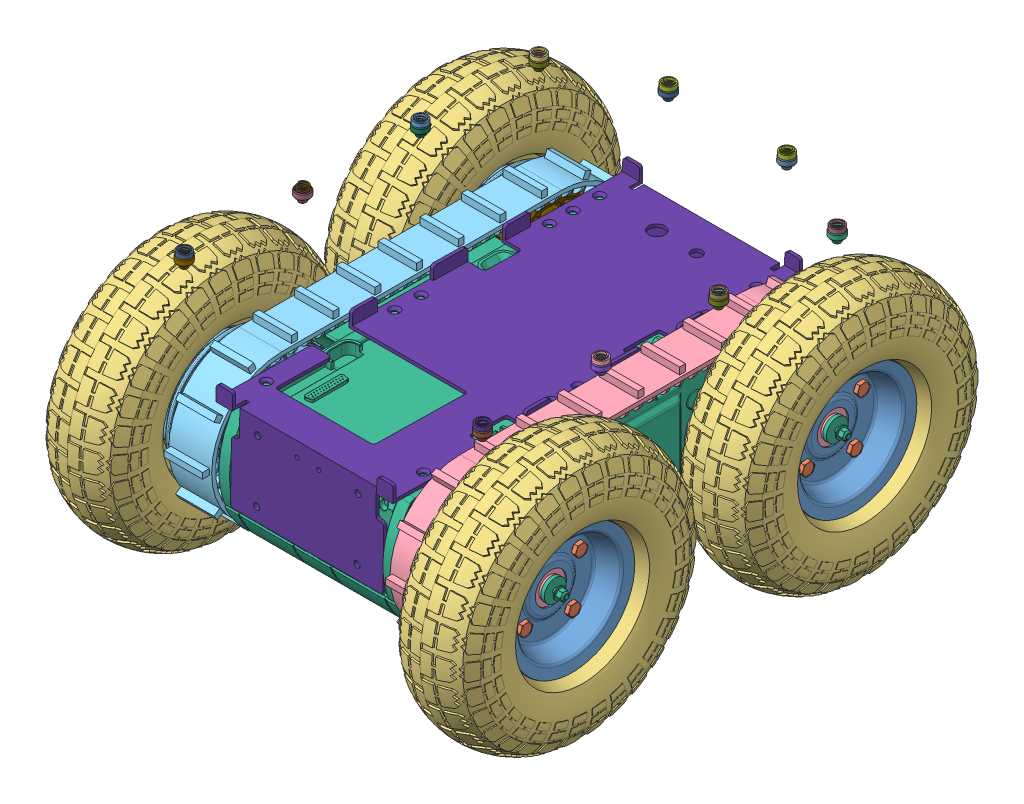
SolidWorks assembly RD_Payload_Rev_A, configuration Default. Lengths in mm.
Overall size (444.69 367.29 650.79).
94 component instances, 59 part files, 0 mates.
Components (placement in the parent):
- RD_Payload_Rev_A.step-1: RD_Payload_Rev_A.step [Default] at origin size (444.69 371.55 650.79)
  - 10 in Wheel.step-1: 10 in Wheel.step [Default] at (178.555 0 0) x (0 -0.59872 0.800958) z (-1 0 0) size (260.79 263.33 83.58)
    - Hub Outer.step-1: Hub Outer.step [Default] x (1 0 0) z (0 0 -1) size (127 127 25.4)
    - Bolt M8x14mm.step-1: Bolt M8x14mm.step [Default] at (0 34.925 -7.0104) x (1 0 0) z (0 -1 0) size (11.71 18.58 13.52)
    - Bolt M8x14mm.step-2: Bolt M8x14mm.step [Default] at (-34.925 0 -7.0104) x (1 0 0) z (0 -1 0) size (11.71 18.58 13.52)
    - Bolt M8x14mm.step-3: Bolt M8x14mm.step [Default] at (0 -34.925 -7.0104) x (1 0 0) z (0 -1 0) size (11.71 18.58 13.52)
    - Bolt M8x14mm.step-4: Bolt M8x14mm.step [Default] at (34.925 0 -7.0104) x (1 0 0) z (0 -1 0) size (11.71 18.58 13.52)
    - Tire.step-1: Tire.step [Default] x (0 0 -1) z (-0.99993 -0.011854 0) size (83.58 260.3 257.72)
    - Bearing.step-1: Bearing.step [Default] at (0 0 -2.159) x (0.59872 -0.800958 0) z (0 0 -1) size (37.59 37.59 12.4)
    - ModifiedWheelHub.step-1: ModifiedWheelHub.step [Default] at (-0.127 0 22.847) x (0 0 -1) z (1 0 0) size (30.5 125 125)
  - 10 in Wheel_1.step-1: 10 in Wheel_1.step [Default] at (180.555 0 -283.5) x (0 -0.59872 0.800958) z (-1 0 0) size (260.79 263.33 83.58)
    - Hub Outer.step-1: Hub Outer.step [Default] x (1 0 0) z (0 0 -1) size (127 127 25.4)
    - Bolt M8x14mm.step-1: Bolt M8x14mm.step [Default] at (0 34.925 -7.0104) x (1 0 0) z (0 -1 0) size (11.71 18.58 13.52)
    - Bolt M8x14mm.step-2: Bolt M8x14mm.step [Default] at (-34.925 0 -7.0104) x (1 0 0) z (0 -1 0) size (11.71 18.58 13.52)
    - Bolt M8x14mm.step-3: Bolt M8x14mm.step [Default] at (0 -34.925 -7.0104) x (1 0 0) z (0 -1 0) size (11.71 18.58 13.52)
    - Bolt M8x14mm.step-4: Bolt M8x14mm.step [Default] at (34.925 0 -7.0104) x (1 0 0) z (0 -1 0) size (11.71 18.58 13.52)
    - Tire.step-1: Tire.step [Default] x (0 0 -1) z (-0.99993 -0.011854 0) size (83.58 260.3 257.72)
    - Bearing.step-1: Bearing.step [Default] at (0 0 -2.159) x (0.59872 -0.800958 0) z (0 0 -1) size (37.59 37.59 12.4)
    - ModifiedWheelHub.step-1: ModifiedWheelHub.step [Default] at (-0.127 0 22.847) x (0 0 -1) z (1 0 0) size (30.5 125 125)
  - 10 in Wheel_2.step-1: 10 in Wheel_2.step [Default] at (-180.555 0 -283.5) x (0 -0.800958 0.59872) z (1 0 0) size (260.79 263.33 83.58)
    - Hub Outer.step-1: Hub Outer.step [Default] x (1 0 0) z (0 0 -1) size (127 127 25.4)
    - Bolt M8x14mm.step-1: Bolt M8x14mm.step [Default] at (0 34.925 -7.0104) x (1 0 0) z (0 -1 0) size (11.71 18.58 13.52)
    - Bolt M8x14mm.step-2: Bolt M8x14mm.step [Default] at (-34.925 0 -7.0104) x (1 0 0) z (0 -1 0) size (11.71 18.58 13.52)
    - Bolt M8x14mm.step-3: Bolt M8x14mm.step [Default] at (0 -34.925 -7.0104) x (1 0 0) z (0 -1 0) size (11.71 18.58 13.52)
    - Bolt M8x14mm.step-4: Bolt M8x14mm.step [Default] at (34.925 0 -7.0104) x (1 0 0) z (0 -1 0) size (11.71 18.58 13.52)
    - Tire.step-1: Tire.step [Default] x (0 0 -1) z (-0.99993 -0.011854 0) size (83.58 260.3 257.72)
    - Bearing.step-1: Bearing.step [Default] at (0 0 -2.159) x (0.59872 -0.800958 0) z (0 0 -1) size (37.59 37.59 12.4)
    - ModifiedWheelHub.step-1: ModifiedWheelHub.step [Default] at (-0.127 0 22.847) x (0 0 -1) z (1 0 0) size (30.5 125 125)
  - 10 in Wheel_3.step-1: 10 in Wheel_3.step [Default] at (-178.555 0 0) x (0 -0.800958 0.59872) z (1 0 0) size (260.79 263.33 83.58)
    - Hub Outer.step-1: Hub Outer.step [Default] x (1 0 0) z (0 0 -1) size (127 127 25.4)
    - Bolt M8x14mm.step-1: Bolt M8x14mm.step [Default] at (0 34.925 -7.0104) x (1 0 0) z (0 -1 0) size (11.71 18.58 13.52)
    - Bolt M8x14mm.step-2: Bolt M8x14mm.step [Default] at (-34.925 0 -7.0104) x (1 0 0) z (0 -1 0) size (11.71 18.58 13.52)
    - Bolt M8x14mm.step-3: Bolt M8x14mm.step [Default] at (0 -34.925 -7.0104) x (1 0 0) z (0 -1 0) size (11.71 18.58 13.52)
    - Bolt M8x14mm.step-4: Bolt M8x14mm.step [Default] at (34.925 0 -7.0104) x (1 0 0) z (0 -1 0) size (11.71 18.58 13.52)
    - Tire.step-1: Tire.step [Default] x (0 0 -1) z (-0.99993 -0.011854 0) size (83.58 260.3 257.72)
    - Bearing.step-1: Bearing.step [Default] at (0 0 -2.159) x (0.59872 -0.800958 0) z (0 0 -1) size (37.59 37.59 12.4)
    - ModifiedWheelHub.step-1: ModifiedWheelHub.step [Default] at (-0.127 0 22.847) x (0 0 -1) z (1 0 0) size (30.5 125 125)
  - R&D Payload.step-1: R&D Payload.step [Default] at (7.0458 -116.5686 -486.2193) x (1 0 0) z (0 0.999848 -0.017452) size (435.85 572.37 235.56)
    - R&D Payload Assembly (approx, don't use) v9.step-1: R&D Payload Assembly (approx, don't use) v9.step [Default] at (0 0 150) size (435.85 572.37 129.48)
      - PPatrol Payload v6.step-1: PPatrol Payload v6.step [Default] at (200.9785 -625.114 143.2331) x (0 -1 0) z (-1 0 0) size (572.37 31.75 435.85)
        - 8020-1010-BLACK-1010-BLACK X 72 v1.step-1: 8020-1010-BLACK-1010-BLACK X 72 v1.step [Default] at (-12.6721 -12.7 413.3053) size (25.4 25.4 387.35) (hidden)
        - 8020-1010-BLACK-1010-BLACK X 72 v1 (1).step-1: 8020-1010-BLACK-1010-BLACK X 72 v1 (1).step [Default] at (-25.3721 -12.7 400.6053) x (0 0 -1) z (1 0 0) size (25.4 25.4 523.88) (hidden)
        - 8020-1010-BLACK-1010-BLACK X 72 v1 (2).step-1: 8020-1010-BLACK-1010-BLACK X 72 v1 (2).step [Default] at (-536.5471 -12.7 387.9053) size (25.4 25.4 387.35) (hidden)
        - 8020-1010-BLACK-1010-BLACK X 72 v1 (1) (1).step-1: 8020-1010-BLACK-1010-BLACK X 72 v1 (1) (1).step [Default] at (-637.3851 -12.7 -418.5447) x (0 0 1) z (-1 0 0) size (25.4 25.4 523.88) (hidden)
        - Polycarbonate.step-1: Polycarbonate.step [Default] at origin size (572.37 6.4 435.85) (hidden)
      - Gasket (approximate).step-1: Gasket (approximate).step [Default] at (-17.1019 -288.0369 37.8723) x (1 0 0) z (0 -1 0) size (325.94 3 463.22) (hidden)
      - Component8.step-1: Component8.step [Default] at (-17.1019 -288.0369 37.8723) x (1 0 0) z (0 -1 0) size (99.02 8.47 93.56) (hidden)
      - Component9.step-1: Component9.step [Default] at (-17.1019 -288.0369 37.8723) x (1 0 0) z (0 -1 0) size (13.43 10.76 13.43) (hidden)
      - Component10.step-1: Component10.step [Default] at (-17.1019 -288.0369 37.8723) x (1 0 0) z (0 -1 0) size (10.99 7.47 11.04)
      - Component11.step-1: Component11.step [Default] at (-17.1019 -288.0369 37.8723) x (1 0 0) z (0 -1 0) size (10.99 7.47 11.04) (hidden)
      - Component12.step-1: Component12.step [Default] at (-17.1019 -288.0369 37.8723) x (1 0 0) z (0 -1 0) size (325.94 88.29 30) (hidden)
      - Component13.step-1: Component13.step [Default] at (-17.1019 -288.0369 37.8723) x (1 0 0) z (0 -1 0) size (13.43 10.76 13.43)
      - Component14.step-1: Component14.step [Default] at (-17.1019 -288.0369 37.8723) x (1 0 0) z (0 -1 0) size (10.99 7.47 11.04)
      - Component15.step-1: Component15.step [Default] at (-17.1019 -288.0369 37.8723) x (1 0 0) z (0 -1 0) size (14.52 10.94 14.52)
      - Component16.step-1: Component16.step [Default] at (-17.1019 -288.0369 37.8723) x (1 0 0) z (0 -1 0) size (13.43 10.76 13.43)
      - Component17.step-1: Component17.step [Default] at (-17.1019 -288.0369 37.8723) x (1 0 0) z (0 -1 0) size (10.99 7.47 11.04) (hidden)
      - Component18.step-1: Component18.step [Default] at (-17.1019 -288.0369 37.8723) x (1 0 0) z (0 -1 0) size (14.52 10.94 14.52) (hidden)
      - Component19.step-1: Component19.step [Default] at (-17.1019 -288.0369 37.8723) x (1 0 0) z (0 -1 0) size (13.43 10.76 13.43) (hidden)
      - Component20.step-1: Component20.step [Default] at (-17.1019 -288.0369 37.8723) x (1 0 0) z (0 -1 0) size (10.99 7.47 11.04)
      - Component21.step-1: Component21.step [Default] at (-17.1019 -288.0369 37.8723) x (1 0 0) z (0 -1 0) size (10.99 7.47 11.04)
      - Component22.step-1: Component22.step [Default] at (-17.1019 -288.0369 37.8723) x (1 0 0) z (0 -1 0) size (14.52 10.94 14.52) (hidden)
      - Component23.step-1: Component23.step [Default] at (-17.1019 -288.0369 37.8723) x (1 0 0) z (0 -1 0) size (14.52 10.94 14.52)
      - Component24.step-1: Component24.step [Default] at (-17.1019 -288.0369 37.8723) x (1 0 0) z (0 -1 0) size (10.99 7.47 11.04)
      - Component25.step-1: Component25.step [Default] at (-17.1019 -288.0369 37.8723) x (1 0 0) z (0 -1 0) size (13.43 10.76 13.43) (hidden)
      - Component26.step-1: Component26.step [Default] at (-17.1019 -288.0369 37.8723) x (1 0 0) z (0 -1 0) size (14.52 10.94 14.52)
      - Component27.step-1: Component27.step [Default] at (-17.1019 -288.0369 37.8723) x (1 0 0) z (0 -1 0) size (14.52 10.94 14.52)
      - Component28.step-1: Component28.step [Default] at (-17.1019 -288.0369 37.8723) x (1 0 0) z (0 -1 0) size (13.43 10.76 13.43)
      - Component29.step-1: Component29.step [Default] at (-17.1019 -288.0369 37.8723) x (1 0 0) z (0 -1 0) size (10.99 7.47 11.04)
      - Component30.step-1: Component30.step [Default] at (-17.1019 -288.0369 37.8723) x (1 0 0) z (0 -1 0) size (13.43 10.76 13.43)
      - Component31.step-1: Component31.step [Default] at (-17.1019 -288.0369 37.8723) x (1 0 0) z (0 -1 0) size (10.99 7.47 11.04)
      - Component32.step-1: Component32.step [Default] at (-17.1019 -288.0369 37.8723) x (1 0 0) z (0 -1 0) size (13.43 10.76 13.43)
      - Component33.step-1: Component33.step [Default] at (-17.1019 -288.0369 37.8723) x (1 0 0) z (0 -1 0) size (13.43 10.76 13.43)
      - Component34.step-1: Component34.step [Default] at (-17.1019 -288.0369 37.8723) x (1 0 0) z (0 -1 0) size (10.99 7.47 11.04)
      - Component35.step-1: Component35.step [Default] at (-17.1019 -288.0369 37.8723) x (1 0 0) z (0 -1 0) size (325.94 88.29 403.22) (hidden)
      - Component36.step-1: Component36.step [Default] at (-17.1019 -288.0369 37.8723) x (1 0 0) z (0 -1 0) size (325.94 88.29 30) (hidden)
      - Component37.step-1: Component37.step [Default] at (-17.1019 -288.0369 37.8723) x (1 0 0) z (0 -1 0) size (14.52 10.94 14.52)
      - Component38.step-1: Component38.step [Default] at (-17.1019 -288.0369 37.8723) x (1 0 0) z (0 -1 0) size (13.43 10.76 13.43)
      - Component39.step-1: Component39.step [Default] at (-17.1019 -288.0369 37.8723) x (1 0 0) z (0 -1 0) size (14.52 10.94 14.52)
      - Component40.step-1: Component40.step [Default] at (-17.1019 -288.0369 37.8723) x (1 0 0) z (0 -1 0) size (10.99 7.47 11.04)
      - Component41.step-1: Component41.step [Default] at (-17.1019 -288.0369 37.8723) x (1 0 0) z (0 -1 0) size (14.52 10.94 14.52)
      - Component42.step-1: Component42.step [Default] at (-17.1019 -288.0369 37.8723) x (1 0 0) z (0 -1 0) size (14.52 10.94 14.52)
      - Component43.step-1: Component43.step [Default] at (-17.1019 -288.0369 37.8723) x (1 0 0) z (0 -1 0) size (13.43 10.76 13.43)
      - Component44.step-1: Component44.step [Default] at (-17.1019 -288.0369 37.8723) x (1 0 0) z (0 -1 0) size (13.43 10.76 13.43)
      - Component45.step-1: Component45.step [Default] at (-17.1019 -288.0369 37.8723) x (1 0 0) z (0 -1 0) size (14.52 10.94 14.52)
      - Component46.step-1: Component46.step [Default] at (-17.1019 -288.0369 37.8723) x (1 0 0) z (0 -1 0) size (10.99 7.47 11.04)
      - Component47.step-1: Component47.step [Default] at (-17.1019 -288.0369 37.8723) x (1 0 0) z (0 -1 0) size (14.52 10.94 14.52)
    - Rear Bracket and Payload Spacer (XXXXXX) v2.step-1: Rear Bracket and Payload Spacer (XXXXXX) v2.step [Default] at (-7.0458 -148.6279 107.7511) x (-1 0 0) z (0 1 0) size (179.03 126.19 414.77)
  - 100251_revA.step-1: 100251_revA.step [Default] at (-101.5 0 -283.5) x (0 0.000178 1) z (-1 0 0) size (137.55 138 25)
  - 100251_revA (1).step-1: 100251_revA (1).step [Default] at (-99.5 0 0) x (0 0.53745 -0.843296) z (-1 0 0) size (137.55 138 25)
  - 100251_revA (2).step-1: 100251_revA (2).step [Default] at (101.5 0 -283.5) x (0 0.53745 0.843296) z (1 0 0) size (137.55 138 25)
  - 100251_revA (3).step-1: 100251_revA (3).step [Default] at (99.5 0 0) x (0 0.000178 -1) z (1 0 0) size (137.55 138 25)
  - WODDEN_track_inner_simplified.step-1: WODDEN_track_inner_simplified.step [Default] at (112 0 -141.75) x (0 0 -1) z (1 0 0) size (439.5 156 43.5)
  - WODDEN_track_inner_simplified (1).step-1: WODDEN_track_inner_simplified (1).step [Default] at (-112 0 -141.75) x (0 0 -1) z (1 0 0) size (439.5 156 43.5)
  - 4WD_R&D_Plate_workspace.step-1: 4WD_R&D_Plate_workspace.step [Default] at origin size (400.01 131.58 418.13)
